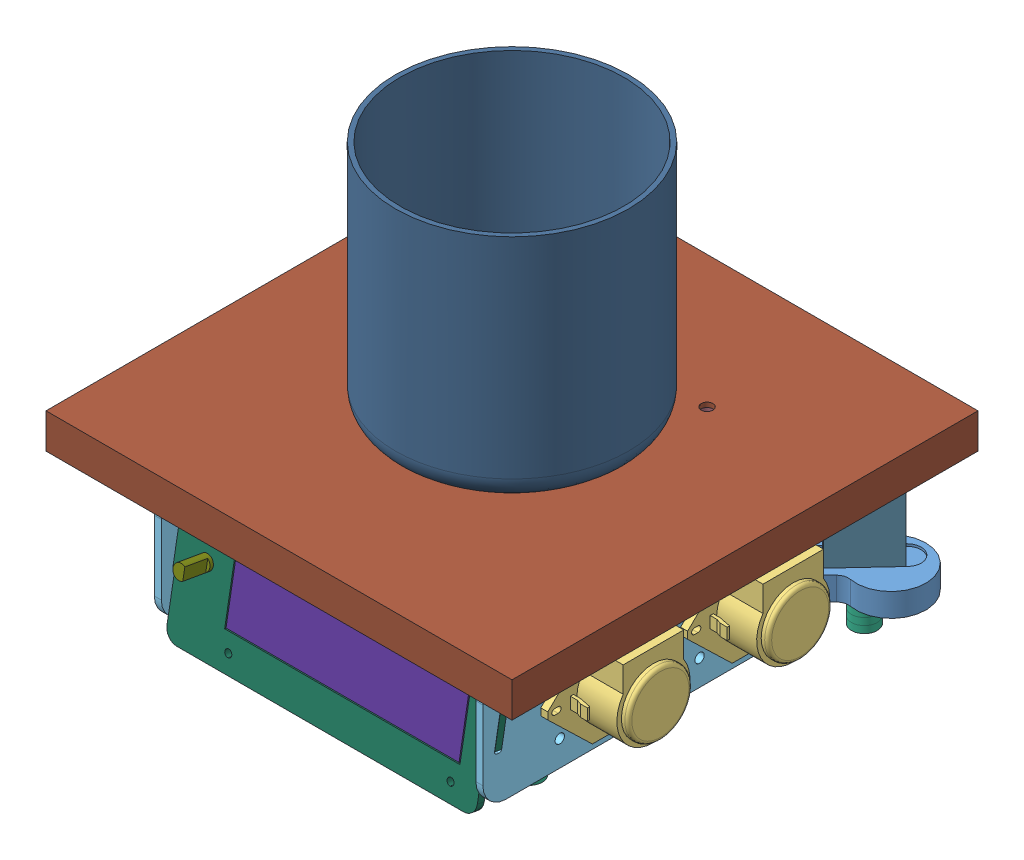
SolidWorks assembly A Bioreactor v3, configuration Défaut. Lengths in mm.
Overall size (200 181.6 200).
48 component instances, 17 part files, 67 mates.
Components (placement in the parent):
- Support v3.1-1: Support v3.1 [Défaut] at (0 10 0) x (0 0 -1) z (1 0 0) size (156.32 10 163.82)
- Arduino-1: Arduino [Défaut] at (-50.2 0 42.5) x (0 0 1) z (0 1 0) size (84.9 100.5 10)
- peristaltic pump-1: peristaltic pump [Défaut] at (70.5 29 -30) x (0 0 1) z (1 0 0) size (56.3 60 67.3)
- peristaltic pump-2: peristaltic pump [Défaut] at (70.5 29 30) x (0 0 1) z (1 0 0) size (56.3 60 67.3)
- Stepper 33-1: Stepper 33 [Défaut] at (0 19 0) x (1 0 0) z (0 1 0) size (42 42 56)
- peristaltic pump-3: peristaltic pump [Défaut] at (-70.5 29 -30) x (0 0 -1) z (-1 0 0) size (56.3 60 67.3)
- peristaltic pump-4: peristaltic pump [Défaut] at (-70.5 29 30) x (0 0 -1) z (-1 0 0) size (56.3 60 67.3)
- Pump support-1: Pump support [Défaut] at (67.5 54 0) x (0 0 1) z (1 0 0) size (140 50 3)
- Foot-1: Foot [Défaut] at (-57.5 10 -70) x (0.923728 0 -0.383049) z (0 -1 0) size (11 11 3)
- Foot-2: Foot [Défaut] at (72.9738 10 -78.2548) x (0.923728 0 -0.383049) z (0 -1 0) size (11 11 3)
- Foot-3: Foot [Défaut] at (-57.5 10 50) x (0.923728 0 -0.383049) z (0 -1 0) size (11 11 3)
- Foot-4: Foot [Défaut] at (57.5 10 50) x (0.923728 0 -0.383049) z (0 -1 0) size (11 11 3)
- Foot-5: Foot [Défaut] at (57.5 7 50) x (0.923728 0 -0.383049) z (0 -1 0) size (11 11 3)
- Foot-6: Foot [Défaut] at (57.5 4 50) x (0.923728 0 -0.383049) z (0 -1 0) size (11 11 3)
- Foot-7: Foot [Défaut] at (57.5 1 50) x (0.923728 0 -0.383049) z (0 -1 0) size (11 11 3)
- Foot-9: Foot [Défaut] at (-57.5 7 50) x (0.923728 0 -0.383049) z (0 -1 0) size (11 11 3)
- Foot-10: Foot [Défaut] at (-57.5 4 50) x (0.923728 0 -0.383049) z (0 -1 0) size (11 11 3)
- Foot-11: Foot [Défaut] at (-57.5 1 50) x (0.923728 0 -0.383049) z (0 -1 0) size (11 11 3)
- Foot-13: Foot [Défaut] at (-57.5 7 -70) x (0.923728 0 -0.383049) z (0 -1 0) size (11 11 3)
- Foot-14: Foot [Défaut] at (-57.5 4 -70) x (0.923728 0 -0.383049) z (0 -1 0) size (11 11 3)
- Foot-15: Foot [Défaut] at (-57.5 1 -70) x (0.923728 0 -0.383049) z (0 -1 0) size (11 11 3)
- Foot-17: Foot [Défaut] at (72.9738 7 -78.2548) x (0.923728 0 -0.383049) z (0 -1 0) size (11 11 3)
- Foot-18: Foot [Défaut] at (72.9738 4 -78.2548) x (0.923728 0 -0.383049) z (0 -1 0) size (11 11 3)
- Foot-19: Foot [Défaut] at (72.9738 1 -78.2548) x (0.923728 0 -0.383049) z (0 -1 0) size (11 11 3)
- A magnet support v2B-1: A magnet support v2B [Défaut] at (1.1743 42.4966 0.0306) x (0.99966 0 0.026085) z (0 1 0) size (50.93 50.93 20)
  - magnet motor v2-1: magnet motor v2 [Défaut] at (-1.1747 0.497 10) size (20.8 20.8 15.5) (hidden)
  - magnet support v2B-1: magnet support v2B [Défaut] at (-1.1747 0 28.0034) size (50.93 50.93 4.61) (hidden)
- A magnet support v2T-1: A magnet support v2T [Défaut] at (0.7221 50.9889 4.2997) x (0.012696 0 -0.999919) z (0 1 0) size (51.6 51.6 20.23)
  - magnet support v2T-1: magnet support v2T [Défaut] at (4.2902 0.7767 30.6111) x (-0.99991 0.013392 0) z (0 0 -1) size (50.93 50.93 20.23) (hidden)
- recipient-1: recipient [Défaut] at (0 76.6 0) size (100 100 100)
- case top cover-1: case top cover [Défaut] at (100 76.6 100) x (-1 0 0) z (0 -1 0) size (200 200 15)
- weight sensor-1: weight sensor [Défaut] at (22.1493 71.6 -32.9898) x (0.731354 0 0.681998) z (0.681998 0 -0.731354) size (14.1 14.1 80.2)
- Weight sensor support-1: Weight sensor support [Défaut] at (35.2818 74.6 -37.8351) x (0.681998 0 -0.731354) z (-0.731354 0 -0.681998) size (40 3 30)
- Weight sensor holder-1: Weight sensor holder [Défaut] at (85.8413 59 -83.2558) x (0 -1 0) z (-0.731354 0 -0.681998) size (40 25 12)
- Foot-22: Foot [Défaut] at (57.5 7 -61.6612) x (1 0 0) z (0 1 0) size (11 11 3)
- Foot-23: Foot [Défaut] at (57.5 4 -61.6612) x (1 0 0) z (0 1 0) size (11 11 3)
- Foot-24: Foot [Défaut] at (57.5 1 -61.6612) x (1 0 0) z (0 1 0) size (11 11 3)
- Foot-25: Foot [Défaut] at (57.5 -2 -61.6612) x (1 0 0) z (0 1 0) size (11 11 3)
- Foot-27: Foot [Défaut] at (57.5 -5 -61.6612) x (1 0 0) z (0 1 0) size (11 11 3)
- Foot-28: Foot [Défaut] at (72.9738 -2 -78.2548) x (0.923728 0 -0.383049) z (0 -1 0) size (11 11 3)
- Foot-29: Foot [Défaut] at (-57.5 -2 -70) x (0.923728 0 -0.383049) z (0 -1 0) size (11 11 3)
- Foot-30: Foot [Défaut] at (-57.5 -2 50) x (0.923728 0 -0.383049) z (0 -1 0) size (11 11 3)
- Foot-31: Foot [Défaut] at (57.5 -2 50) x (0.923728 0 -0.383049) z (0 -1 0) size (11 11 3)
- Pump support-3: Pump support [Défaut] at (-70.5 54 0) x (0 0 1) z (1 0 0) size (140 50 3)
- Screen support v1.1-1: Screen support v1.1 [Défaut] at (-0.1 33.3098 73.2106) x (1 0 0) z (0 0.173648 0.984808) size (141.2 70 3)
- A screen button-1: A screen button [Défaut] at (-53.5523 27.1565 50.9408) x (0 0.984808 -0.173648) z (0 0.173648 0.984808) size (60 117 25)
  - button-1: button [Défaut] at (-0.3073 1.0477 12.5) size (15 11 25)
  - screen-1: screen [Défaut] at (-27.8073 -10.4523 12.5) x (0 -1 0) z (0 0 1) size (100 60 13.5)
Mates (geometry in assembly coordinates):
- Coaxiale6: concentric aligned: cylinder of Support v3.1-1 through (16.8 20 -16.8) axis (0 1 0) radius 1; cylinder of Stepper 33-1 through (16.8 19 -16.8) axis (0 1 0) radius 1
- Coaxiale7: concentric aligned: cylinder of Support v3.1-1 through (16.8 20 16.8) axis (0 1 0) radius 1; cylinder of Stepper 33-1 through (16.8 19 16.8) axis (0 1 0) radius 1
- Coïncidente4: coincident anti-aligned: plane of Support v3.1-1 through (0 19 0) normal (0 1 0); plane of Stepper 33-1 through (0 19 0) normal (0 -1 0)
- Coïncidente5: coincident anti-aligned: plane of Arduino-1 through (-50.2 10 42.5) normal (0 1 0); plane of Support v3.1-1 through (-57.5 10 -70) normal (0 -1 0)
- Tangent1: tangent anti-aligned: cylinder of peristaltic pump-1 through (32 29 -30) axis (1 0 0) radius 14; plane of Support v3.1-1 through (26.5 15 -37) normal (0 1 0)
- Coaxiale8: concentric anti-aligned: cylinder of peristaltic pump-1 through (32 29 -30) axis (1 0 0) radius 14; cylinder of Pump support-1 through (70.5 29 -30) axis (-1 0 0) radius 15
- Coaxiale9: concentric anti-aligned: cylinder of peristaltic pump-2 through (32 29 30) axis (1 0 0) radius 14; cylinder of Pump support-1 through (70.5 29 30) axis (-1 0 0) radius 15
- Coïncidente6: coincident anti-aligned: plane of Support v3.1-1 through (67.5 20 50) normal (1 0 0); plane of Pump support-1 through (67.5 53 -25.8804) normal (-1 0 0)
- Coïncidente7: coincident anti-aligned: plane of Support v3.1-1 through (-67.5 20 -58.4985) normal (-1 0 0); plane of ? through (-67.5 14 -47) normal (1 0 0)
- Coaxiale10: concentric anti-aligned: cylinder of peristaltic pump-3 through (-34 29 -30) axis (-1 0 0) radius 14; cylinder of ? through (-72.5 29 -30) axis (1 0 0) radius 15
- Coaxiale11: concentric anti-aligned: cylinder of peristaltic pump-4 through (-34 29 30) axis (-1 0 0) radius 14; cylinder of ? through (-72.5 29 30) axis (1 0 0) radius 15
- Coaxiale12: concentric aligned: cylinder of Support v3.1-1 through (-57.5 20 -70) axis (0 1 0) radius 3; cylinder of Foot-1 through (-57.5 7 -70) axis (0 1 0) radius 2.5
- Coïncidente8: coincident anti-aligned: plane of Support v3.1-1 through (-57.5 10 -70) normal (0 -1 0); plane of Foot-1 through (-57.5 10 -70) normal (0 1 0)
- Coaxiale13: concentric aligned: cylinder of Support v3.1-1 through (-57.5 20 50) axis (0 1 0) radius 3; cylinder of Foot-3 through (-57.5 7 50) axis (0 1 0) radius 2.5
- Coïncidente9: coincident anti-aligned: plane of Support v3.1-1 through (-57.5 10 -70) normal (0 -1 0); plane of Foot-3 through (-57.5 10 50) normal (0 1 0)
- Coaxiale14: concentric aligned: cylinder of Support v3.1-1 through (72.9738 20 -78.2548) axis (0 1 0) radius 3; cylinder of Foot-2 through (72.9738 7 -78.2548) axis (0 1 0) radius 2.5
- Coïncidente10: coincident anti-aligned: plane of Support v3.1-1 through (-57.5 10 -70) normal (0 -1 0); plane of Foot-2 through (72.9738 10 -78.2548) normal (0 1 0)
- Coaxiale15: concentric aligned: cylinder of Support v3.1-1 through (57.5 20 50) axis (0 1 0) radius 3; cylinder of Foot-4 through (57.5 7 50) axis (0 1 0) radius 2.5
- Coïncidente11: coincident anti-aligned: plane of Support v3.1-1 through (-57.5 10 -70) normal (0 -1 0); plane of Foot-4 through (57.5 10 50) normal (0 1 0)
- Coïncidente12: coincident anti-aligned: plane of peristaltic pump-4 through (-72.5 29 30) normal (1 0 0); plane of ? through (-72.5 14 -47) normal (-1 0 0)
- Coaxiale16: concentric anti-aligned: cylinder of A magnet support v2B-1/magnet support v2B-1 through (14.5062 75.0001 -13.7684) axis (0 -1 0) radius 6.05; cylinder of A magnet support v2T-1/magnet support v2T-1 through (14.5062 78.5999 -13.7684) axis (0 1 0) radius 6.05
- Parallèle1: parallel anti-aligned: cylinder of A magnet support v2B-1/magnet support v2B-1 through (-13.7684 75.0001 -14.5062) axis (0 -1 0) radius 6.05; cylinder of A magnet support v2T-1/magnet support v2T-1 through (-14.5062 78.5999 13.7684) axis (0 1 0) radius 6.05
- Coaxiale18: concentric anti-aligned: cylinder of Stepper 33-1 through (0 75 0) axis (0 -1 0) radius 2.5; cylinder of A magnet support v2B-1/magnet motor v2-1 through (0 79.1408 0) axis (0 1 0) radius 3.4
- Coaxiale19: concentric anti-aligned: cylinder of A magnet support v2B-1/magnet support v2B-1 through (-13.7684 75.0001 -14.5062) axis (0 -1 0) radius 6.05; cylinder of A magnet support v2T-1/magnet support v2T-1 through (-13.7684 78.5999 -14.5062) axis (0 1 0) radius 6.05
- Coïncidente13: coincident aligned: plane of Stepper 33-1 through (0 75 0) normal (0 1 0); plane of A magnet support v2B-1/magnet support v2B-1 through (21.7593 75 -20.6526) normal (0 1 0)
- Coïncidente19: coincident anti-aligned: plane of recipient-1 through (0 76.6 0) normal (0 -1 0); plane of case top cover-1 through (100 76.6 100) normal (0 1 0)
- Coaxiale20: concentric aligned: cylinder of A magnet support v2B-1/magnet motor v2-1 through (0 79.1408 0) axis (0 1 0) radius 7.4; cylinder of recipient-1 through (0 78.6 0) axis (0 1 0) radius 50
- Coïncidente20: coincident anti-aligned: plane of A magnet support v2T-1/magnet support v2T-1 through (-21.7593 78.6 20.6526) normal (0 -1 0); plane of recipient-1 through (38 78.6 0) normal (0 1 0)
- Coïncidente21: coincident aligned: plane of ? through (101.013 -193.8813 147.0054) normal (0 0 1); plane of ? through (94.7284 -170.5827 147.0054) normal (0 0 1)
- Coïncidente23: coincident anti-aligned: plane of case top cover-1 through (100 74.6 100) normal (0 -1 0); plane of Weight sensor support-1 through (31.8719 74.6 -34.1784) normal (0 1 0)
- Coïncidente24: coincident anti-aligned: plane of weight sensor-1 through (76.8456 71.6 -91.6444) normal (0 1 0); plane of Weight sensor support-1 through (31.8719 71.6 -34.1784) normal (0 -1 0)
- Coaxiale25: concentric anti-aligned: cylinder of weight sensor-1 through (40.3968 71.6 -43.3203) axis (0 -1 0) radius 2; cylinder of Weight sensor support-1 through (40.3968 71.6 -43.3203) axis (0 1 0) radius 2.5
- Coaxiale26: concentric anti-aligned: cylinder of weight sensor-1 through (30.1669 71.6 -32.35) axis (0 -1 0) radius 2; cylinder of Weight sensor support-1 through (30.1669 71.6 -32.35) axis (0 1 0) radius 2.5
- Coïncidente27: coincident anti-aligned: plane of Support v3.1-1 through (57.9699 19 -62.1651) normal (0 1 0); plane of Weight sensor holder-1 through (77.065 19 -91.4398) normal (0 -1 0)
- Coïncidente28: coincident anti-aligned: plane of weight sensor-1 through (76.8456 59 -91.6444) normal (0 -1 0); plane of Weight sensor holder-1 through (77.065 59 -91.4398) normal (0 1 0)
- Coïncidente34: coincident anti-aligned: plane of ? through (-61.0648 0 -72.7742) normal (0 -1 0); plane of assembly through (0 0 0) normal (0 1 0)
- Distance10: distance = 21 mm anti-aligned: plane of assembly through (0 0 0) normal (1 0 0); plane of Stepper 33-1 through (-21 30.9 -16.9) normal (-1 0 0)
- Distance11: distance = 21 mm anti-aligned: plane of Stepper 33-1 through (-16.9 30.9 -21) normal (0 0 -1); plane of assembly through (0 0 0) normal (0 0 1)
- Distance13: distance = 100 mm aligned: plane of case top cover-1 through (100 61.6 100) normal (1 0 0); plane of assembly through (0 0 0) normal (1 0 0)
- Coaxiale27: concentric aligned: cylinder of weight sensor-1 through (67.8132 71.6 -72.7207) axis (0 -1 0) radius 1.5; cylinder of Weight sensor holder-1 through (67.8132 19 -72.7207) axis (0 -1 0) radius 2
- Coaxiale28: concentric aligned: cylinder of weight sensor-1 through (78.0431 71.6 -83.691) axis (0 -1 0) radius 1.5; cylinder of Weight sensor holder-1 through (78.0431 19 -83.691) axis (0 -1 0) radius 2
- Coïncidente35: coincident anti-aligned: plane of Support v3.1-1 through (-57.5 10 -70) normal (0 -1 0); plane of Foot-22 through (57.5 10 -61.6612) normal (0 1 0)
- Coaxiale29: concentric anti-aligned: cylinder of Support v3.1-1 through (57.5 20 -61.6612) axis (0 1 0) radius 3; cylinder of Foot-22 through (57.5 10 -61.6612) axis (0 -1 0) radius 2.5
- Parallèle2: parallel aligned: cylinder of peristaltic pump-1 through (83.5 69 -39) axis (0 -1 0) radius 2; cylinder of Stepper 33-1 through (0 75 0) axis (0 -1 0) radius 2.5
- Distance14: distance = 57 mm anti-aligned: plane of ? through (-72.5 44 -57) normal (0 0 -1); plane of assembly through (0 0 0) normal (0 0 1)
- Coaxiale32: concentric anti-aligned: cylinder of Support v3.1-1 through (78.0431 19 -83.691) axis (0 1 0) radius 1.5; cylinder of Weight sensor holder-1 through (78.0431 19 -83.691) axis (0 -1 0) radius 2
- Distance15: distance = 100 mm anti-aligned: plane of case top cover-1 through (100 61.6 -100) normal (0 0 -1); plane of assembly through (0 0 0) normal (0 0 1)
- Coaxiale33: concentric anti-aligned: cylinder of Support v3.1-1 through (67.8132 19 -72.7207) axis (0 1 0) radius 1.5; cylinder of Weight sensor holder-1 through (67.8132 19 -72.7207) axis (0 -1 0) radius 2
- Distance16: distance = 10 mm anti-aligned: plane of Support v3.1-1 through (-57.5 10 -70) normal (0 -1 0); plane of assembly through (0 0 0) normal (0 1 0)
- Coïncidente36: coincident anti-aligned: plane of Support v3.1-1 through (-57.5 20 -70) normal (0 1 0); plane of ? through (67.5 20 50) normal (0 -1 0)
- Distance17: distance = 57 mm anti-aligned: plane of Pump support-1 through (70.5 14 -57) normal (0 0 -1); plane of assembly through (0 0 0) normal (0 0 1)
- Coïncidente41: coincident anti-aligned: plane of peristaltic pump-1 through (70.5 29 -30) normal (-1 0 0); plane of Pump support-1 through (70.5 53 -25.8804) normal (1 0 0)
- Coaxiale36: concentric anti-aligned: cylinder of Support v3.1-1 through (-47.1 20 -36.6) axis (0 1 0) radius 1; cylinder of Arduino-1 through (-47.1 10 -36.6) axis (0 -1 0) radius 1
- Coaxiale37: concentric anti-aligned: cylinder of Support v3.1-1 through (-47.1 20 36.6) axis (0 1 0) radius 1; cylinder of Arduino-1 through (-47.1 10 36.6) axis (0 -1 0) radius 1
- Coïncidente43: coincident: plane of Support v3.1-1 through (-57.5 20 80) normal (0 0 1); line of ? through (67.5 20 80) axis (-1 0 0)
- Coïncidente44: coincident aligned: plane of Support v3.1-1 through (67.5 20 70) normal (1 0 0); plane of ? through (67.5 25.2076 75.276) normal (1 0 0)
- Distance18: distance = 7.5 mm aligned: plane of A screen button-1/screen-1 through (60 27.3681 79.4897) normal (1 0 0); plane of ? through (67.5 21 80) normal (1 0 0)
- Coïncidente55: coincident anti-aligned: plane of Support v3.1-1 through (-57.5 20 70) normal (0 0 1); plane of ? through (2.5 33 70) normal (0 0 -1)
- Coïncidente56: coincident aligned: plane of Support v3.1-1 through (-67.5 20 50) normal (-1 0 0); plane of ? through (-67.5 3.1 89) normal (-1 0 0)
- Coïncidente57: coincident anti-aligned: plane of Support v3.1-1 through (-57.5 20 60) normal (0 0 1); plane of ? through (62.6 63 60) normal (0 0 -1)
- Distance24: distance = 3 mm aligned: plane of ? through (62.6 -2 64) normal (0 -1 0); plane of Foot-30 through (-57.5 -5 50) normal (0 -1 0)
- Distance25: distance = 0.5 mm: plane of A screen button-1/screen-1 through (-43.1 14.1346 79.638) normal (0 -0.984808 0.173648); plane of Screen support v1.1-1 through (-43.6 13.6422 79.7248) normal (0 0.984808 -0.173648)
- Distance26: distance = 0.5 mm: plane of A screen button-1/screen-1 through (56.9 2.6368 72.0188) normal (1 0 0); plane of Screen support v1.1-1 through (57.4 54.0193 72.6052) normal (-1 0 0)
- Coïncidente61: coincident aligned: plane of Pump support-1 through (70.5 53 -25.8804) normal (1 0 0); plane of Screen support v1.1-1 through (70.5 43.6788 74.4286) normal (1 0 0)
- Coïncidente63: coincident anti-aligned: plane of Pump support-1 through (70.5 23.4617 74.9471) normal (0 0.173648 0.984808); plane of Screen support v1.1-1 through (-61.7 62.854 68.0012) normal (0 -0.173648 -0.984808)
- Distance27: distance = 1 mm anti-aligned: plane of Screen support v1.1-1 through (68.5 23.9826 77.9015) normal (0 -0.984808 0.173648); plane of Pump support-1 through (70.5 22.6505 76.1056) normal (0 0.984808 -0.173648)
- Coïncidente66: coincident aligned: plane of Screen support v1.1-1 through (-61.7 63.3749 70.9556) normal (0 0.173648 0.984808); plane of A screen button-1/screen-1 through (-43.1 4.2865 81.3745) normal (0 0.173648 0.984808)
